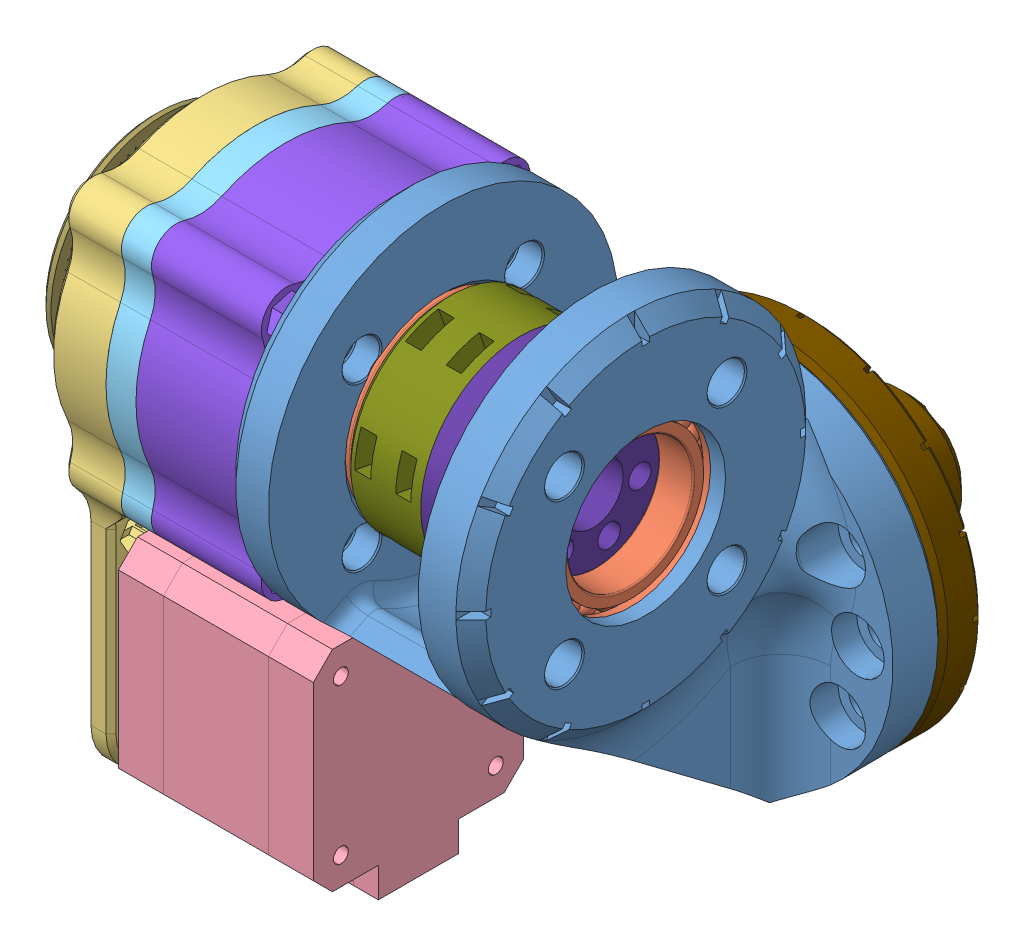
SolidWorks assembly Gelenk_2_V2.0, configuration Standard. Lengths in mm.
Overall size (123 119 108.46).
31 component instances, 18 part files, 19 mates.
Components (placement in the parent):
- Frame_Gelenk_2-1: Frame_Gelenk_2 [Standard] at origin size (70 105 80)
- 6805_Radial_Bearring-1: 6805_Radial_Bearring [Standard] at (10.5 35 45) x (0 0.903849 0.427851) z (0 -0.427851 0.903849) size (37 7 37)
- Assembly_Strain_Wave_Gelenk_2-1: Assembly_Strain_Wave_Gelenk_2 [Standard] at (-69 35 45) x (0 -1 0) z (-1 0 0) size (115.44 62.89 63)
  - Circular_Spline_G2-1: Circular_Spline_G2 [Standard] at origin size (108 60 11.5)
  - motor-1: motor [Default] at (57 0 -44) x (1 0 0) z (0 -1 0) size (48 63 42)
  - 6805_Radial_Bearring-1: 6805_Radial_Bearring [Standard] x (1 0 0) z (0 -1 0) size (37 7 37)
  - Circular_Spline_Teeth_G2-1: Circular_Spline_Teeth_G2 [Standard] at (0 0 -16) size (60 60 7.5)
  - Flex_Spline_G2-1: Flex_Spline_G2 [Standard] at (0 0 -24.25) size (46.35 46.38 14.25)
  - Flex_Spline_Case_G2-1: Flex_Spline_Case_G2 [Standard] at (0 0 -16) x (0.983463 0.181111 0) z (0 0 1) size (54 54 13.5)
  - Circular_Spline_Case_G2-1: Circular_Spline_Case_G2 [Standard] at (0 0 -39.5) size (60 60 23.5)
  - Strain_Wave_Kupplung_G2-1: Strain_Wave_Kupplung_G2 [Standard] at (0 0 -29.5) x (-1 0 0) z (0 0 -1) size (28 28 10)
  - 6805_Radial_Bearring-2: 6805_Radial_Bearring [Standard] at (0 0 -29.5) x (0.401765 -0.915743 0) z (-0.915743 -0.401765 0) size (37 7 37)
  - socket head thin cap screw_din-1: socket head thin cap screw_din [DIN 7984 - M4 x 25 --- 14N] at (21.9203 21.9203 -0.2) x (0 0 -1) z (1 0 0) size (27.8 7 7)
  - socket head thin cap screw_din-2: socket head thin cap screw_din [DIN 7984 - M3 x 20 --- 12N] at (41.5 15.5 -1) x (0 0 -1) z (1 0 0) size (22 5.5 5.5)
  - socket head thin cap screw_din-3: socket head thin cap screw_din [DIN 7984 - M4 x 25 --- 14N] at (-21.9203 21.9203 -0.2) x (0 0 -1) z (0 1 0) size (27.8 7 7)
  - socket head thin cap screw_din-4: socket head thin cap screw_din [DIN 7984 - M4 x 25 --- 14N] at (-21.9203 -21.9203 -0.2) x (0 0 -1) z (-1 0 0) size (27.8 7 7)
  - socket head thin cap screw_din-5: socket head thin cap screw_din [DIN 7984 - M4 x 25 --- 14N] at (21.9203 -21.9203 -0.2) x (0 0 -1) z (0 -1 0) size (27.8 7 7)
  - socket head thin cap screw_din-6: socket head thin cap screw_din [DIN 7984 - M3 x 20 --- 12N] at (41.5 -15.5 -1) x (0 0 -1) z (0 1 0) size (22 5.5 5.5)
  - socket head thin cap screw_din-7: socket head thin cap screw_din [DIN 7984 - M3 x 20 --- 12N] at (72.5 -15.5 -1) x (0 0 -1) z (-1 0 0) size (22 5.5 5.5)
  - socket head thin cap screw_din-8: socket head thin cap screw_din [DIN 7984 - M3 x 20 --- 12N] at (72.5 15.5 -1) x (0 0 -1) z (0 -1 0) size (22 5.5 5.5)
  - Zahnriemenscheibe_Base_Motor-1: Zahnriemenscheibe_Base_Motor [Standard] at (57 0 14) x (1 0 0) z (0 1 0) size (13 14 13)
  - Gearing_Circular_Spline_G2-1: Gearing_Circular_Spline_G2 [Standard] at (0 0 9) size (45 45 12.5)
  - Wave_Generator_Strain_Wave_2_V2-1: Wave_Generator_Strain_Wave_2_V2 [Standard] at (0 0 -10.2) x (-1 0 0) z (0 0 -1) size (34 40.86 20.7)
    - G2_Wave_Generator_1-1: G2_Wave_Generator_1 [Standard] at origin size (34 39 11.7)
    - G2_Wave_Generator_2-1: G2_Wave_Generator_2 [Standard] at (0 0 10) size (34 39 9)
    - radial ball bearing_68_din-1: radial ball bearing_68_din [DIN 625 - 623 - 8,SI,NC,8_68] at (0 15.5 7) x (0 0 -1) z (0.189164 -0.981945 0) size (4 10 10)
    - socket head thin cap screw_din-1: socket head thin cap screw_din [DIN 7984 - M3 x 10 --- 8.5N] at (0 15.5 1) x (0 0 1) z (-0.432969 0.901409 0) size (12 5.5 5.5)
- 6805_Radial_Bearring-2: 6805_Radial_Bearring [Standard] at (-27 35 45) x (0 1 0) z (0 0 1) size (37 7 37)
- Gelenk_2_Kupplungsbeilagsscheibe_V2-1: Gelenk_2_Kupplungsbeilagsscheibe_V2 [Standard] at (-29.5 35 45) x (0 0.648578 0.761148) z (-1 0 0) size (40 40 25)
- Kupplung_Blocker_G2-1: Kupplung_Blocker_G2 [Standard] at (-4.5 35 45) x (0 -0.648578 -0.761148) z (1 0 0) size (40 40 14.5)
- Kupplungsscheibe_Gelenk_1-1: Kupplungsscheibe_Gelenk_1 [Standard] at (0 0 -8) x (0 0 1) z (0 -1 0) size (28.46 70 70)
Mates (geometry in assembly coordinates):
- Deckungsgleich1: coincident aligned: plane of Frame_Gelenk_2-1 through (0 0 0) normal (0 0 1)
- Deckungsgleich2: coincident aligned: plane of Frame_Gelenk_2-1 through (0 0 0) normal (0 1 0)
- Deckungsgleich3: coincident aligned: plane of Frame_Gelenk_2-1 through (0 0 0) normal (1 0 0)
- Konzentrisch3: concentric anti-aligned: cylinder of Frame_Gelenk_2-1 through (-17.5 35 45) axis (1 0 0) radius 35; cylinder of Assembly_Strain_Wave_Gelenk_2-1/Circular_Spline_Case_G2-1 through (-117.5371 35 45) axis (-1 0 0) radius 30
- Deckungsgleich7: coincident anti-aligned: plane of Frame_Gelenk_2-1 through (-29.5 35 45) normal (-1 0 0); plane of Assembly_Strain_Wave_Gelenk_2-1/Circular_Spline_Case_G2-1 through (-29.5 35 45) normal (1 0 0)
- Konzentrisch4: concentric anti-aligned: cylinder of Frame_Gelenk_2-1 through (-35 51.2635 28.7365) axis (1 0 0) radius 2.25; cylinder of Assembly_Strain_Wave_Gelenk_2-1/Circular_Spline_Case_G2-1 through (-29.5 51.2635 28.7365) axis (-1 0 0) radius 2.25
- Konzentrisch6: concentric aligned: cylinder of Frame_Gelenk_2-1 through (76.7502 35 45) axis (-1 0 0) radius 18.65; cylinder of 6805_Radial_Bearring-1 through (14 35 45) axis (-1 0 0) radius 18.5
- Deckungsgleich10: coincident anti-aligned: plane of Frame_Gelenk_2-1 through (-27 35 45) normal (1 0 0); plane of 6805_Radial_Bearring-2 through (-27 35 62.3) normal (-1 0 0)
- Konzentrisch7: concentric aligned: cylinder of Frame_Gelenk_2-1 through (76.7502 35 45) axis (-1 0 0) radius 18.65; cylinder of 6805_Radial_Bearring-2 through (-23.5 35 45) axis (-1 0 0) radius 18.5
- Konzentrisch8: concentric aligned: cylinder of 6805_Radial_Bearring-2 through (-23.5 35 45) axis (-1 0 0) radius 12.5; cylinder of Gelenk_2_Kupplungsbeilagsscheibe_V2-1 through (-29.5 35 45) axis (-1 0 0) radius 12.35
- Deckungsgleich11: coincident anti-aligned: plane of Assembly_Strain_Wave_Gelenk_2-1/Strain_Wave_Kupplung_G2-1 through (-29.5 35 59) normal (1 0 0); plane of Gelenk_2_Kupplungsbeilagsscheibe_V2-1 through (-29.5 35 45) normal (-1 0 0)
- Deckungsgleich12: coincident anti-aligned: plane of Gelenk_2_Kupplungsbeilagsscheibe_V2-1 through (-4.5 50.223 32.0284) normal (1 0 0); plane of Kupplung_Blocker_G2-1 through (-4.5 35 45) normal (-1 0 0)
- Konzentrisch9: concentric aligned: cylinder of Gelenk_2_Kupplungsbeilagsscheibe_V2-1 through (-29.5 35 45) axis (-1 0 0) radius 20; cylinder of Kupplung_Blocker_G2-1 through (10 35 45) axis (-1 0 0) radius 20
- Konzentrisch10: concentric aligned: cylinder of Gelenk_2_Kupplungsbeilagsscheibe_V2-1 through (-4.5 42.2309 38.8385) axis (-1 0 0) radius 2.25; cylinder of Kupplung_Blocker_G2-1 through (10 42.2309 38.8385) axis (-1 0 0) radius 2.25
- Konzentrisch13: concentric aligned: cylinder of Assembly_Strain_Wave_Gelenk_2-1/Flex_Spline_Case_G2-1 through (-39.5 42.2309 38.8385) axis (-1 0 0) radius 2.25; cylinder of Gelenk_2_Kupplungsbeilagsscheibe_V2-1 through (-4.5 42.2309 38.8385) axis (-1 0 0) radius 2.25
- Konzentrisch18: concentric aligned: cylinder of Frame_Gelenk_2-1 through (0 0 10) axis (0 0 -1) radius 35; cylinder of Kupplungsscheibe_Gelenk_1-1 through (0 0 0) axis (0 0 -1) radius 35
- Deckungsgleich17: coincident anti-aligned: plane of Frame_Gelenk_2-1 through (0 0 0) normal (0 0 -1); plane of Kupplungsscheibe_Gelenk_1-1 through (0 0 0) normal (0 0 1)
- Konzentrisch19: concentric anti-aligned: cylinder of Frame_Gelenk_2-1 through (24.2487 14 15) axis (0 0 -1) radius 3.1; cylinder of Kupplungsscheibe_Gelenk_1-1 through (24.2487 14 -16.7681) axis (0 0 1) radius 3.1
- Deckungsgleich18: coincident anti-aligned: plane of Frame_Gelenk_2-1 through (17.5 35 45) normal (-1 0 0); plane of 6805_Radial_Bearring-1 through (17.5 27.5982 60.6366) normal (1 0 0)
